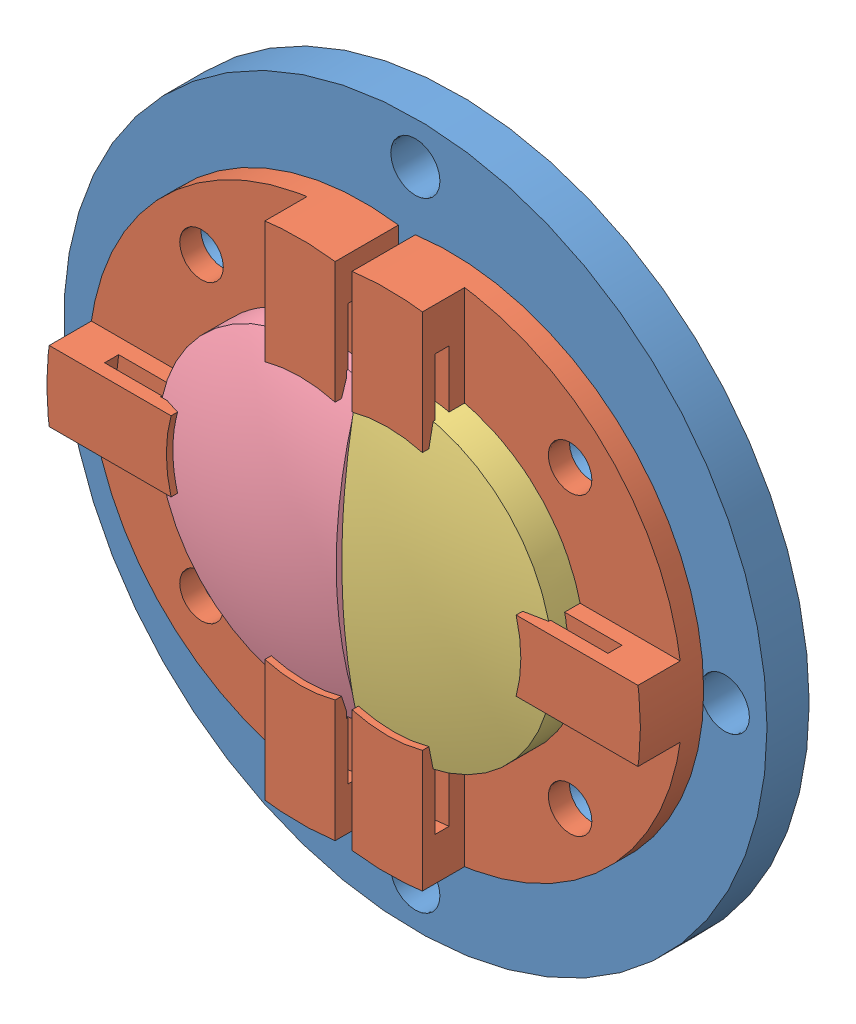
SolidWorks assembly 951.04.01.02.00, configuration Default. Lengths in mm.
Overall size (50 50 8.5).
5 component instances, 4 part files, 12 mates.
Components (placement in the parent):
- 951.04.01.02.01_01-1: 951.04.01.02.01_01 [По умолчанию] at (-10.0916 6.4258 0.9596) size (50 50 3)
- 951.04.01.02.02-1: 951.04.01.02.02 [По умолчанию] at (-7.5916 6.4258 3.9596) size (20.5 36 4.5)
- 951.04.70.00.09-1: 951.04.70.00.09 [Default] at (-7.5916 6.4258 8.9596) x (0 0 -1) z (1 0 0) size (5 22 13.8)
- 951.04.70.00.11-1: 951.04.70.00.11 [Default] at (-13.7916 6.4258 9.4596) x (0 0 -1) z (-1 0 0) size (5.5 22 14.4)
- 951.04.01.02.02-2: 951.04.01.02.02 [По умолчанию] at (-13.7916 6.4258 3.9596) x (-1 0 0) z (0 0 1) size (20.5 36 4.5)
Mates (geometry in assembly coordinates):
- Концентричный1: concentric aligned: cylinder of 951.04.01.02.02-1 through (2.4084 16.9258 4.7096) axis (0 0 1) radius 1.55; cylinder of 951.04.01.02.01_01-1 through (2.4084 16.9258 3.9596) axis (0 0 1) radius 1.0065
- Параллельность1: parallel anti-aligned: plane of 951.04.01.02.02-1 through (-10.0916 -11.3998 3.9596) normal (-1 0 0); plane of assembly through (0 0 0) normal (1 0 0)
- Концентричный2: concentric aligned: cylinder of 951.04.01.02.02-2 through (-23.7916 16.9258 4.7096) axis (0 0 1) radius 1.55; cylinder of 951.04.01.02.01_01-1 through (-23.7916 16.9258 3.9596) axis (0 0 1) radius 1.0065
- Параллельность2: parallel aligned: plane of 951.04.01.02.02-2 through (-11.2916 24.2513 3.9596) normal (1 0 0); plane of assembly through (0 0 0) normal (1 0 0)
- Совпадение1: coincident anti-aligned: plane of 951.04.01.02.01_01-1 through (-10.0916 6.4258 3.9596) normal (0 0 1); plane of 951.04.01.02.02-2 through (-18.6731 6.4258 3.9596) normal (0 0 -1)
- Совпадение2: coincident anti-aligned: plane of 951.04.01.02.01_01-1 through (-10.0916 6.4258 3.9596) normal (0 0 1); plane of 951.04.01.02.02-1 through (-2.71 6.4258 3.9596) normal (0 0 -1)
- Концентричный3: concentric anti-aligned: cylinder of 951.04.01.02.02-1 through (-7.5916 6.4258 5.2596) axis (0 0 -1) radius 11; cylinder of 951.04.70.00.09-1 through (-7.5916 6.4258 28.3285) axis (0 0 1) radius 11
- Концентричный4: concentric anti-aligned: cylinder of 951.04.70.00.11-1 through (-13.7916 6.4258 26.5906) axis (0 0 1) radius 11; cylinder of 951.04.01.02.02-2 through (-13.7916 6.4258 5.2596) axis (0 0 -1) radius 11
- Параллельность3: parallel aligned: plane of 951.04.01.02.02-1 through (-10.0916 -11.3998 3.9596) normal (-1 0 0); plane of 951.04.70.00.09-1 through (-10.3916 6.4258 28.3285) normal (-1 0 0)
- Параллельность4: parallel aligned: plane of 951.04.70.00.11-1 through (-10.3916 6.4258 26.5906) normal (1 0 0); plane of 951.04.01.02.02-2 through (-11.2916 24.2513 3.9596) normal (1 0 0)
- Совпадение4: coincident anti-aligned: plane of 951.04.01.02.01_01-1 through (-10.0916 6.4258 3.9596) normal (0 0 1); plane of 951.04.70.00.11-1 through (-13.7916 -4.5742 3.9596) normal (0 0 -1)
- Совпадение5: coincident anti-aligned: plane of 951.04.01.02.01_01-1 through (-10.0916 6.4258 3.9596) normal (0 0 1); plane of 951.04.70.00.09-1 through (-7.5916 17.4258 3.9596) normal (0 0 -1)
